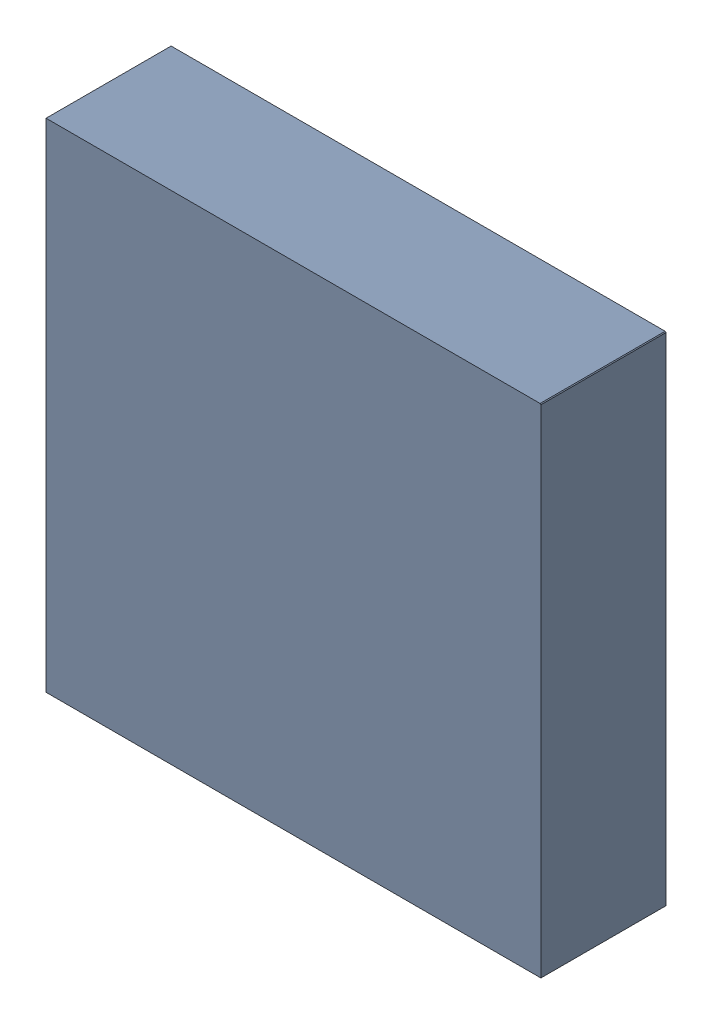
SolidWorks assembly U5, configuration 默认. Lengths in mm.
Overall size (3.17 3.19 0.82).
4 component instances, 2 part files, 0 mates.
Components (placement in the parent):
- 6641442208-1: 6641442208 [默认] at (8.4975 4.6 -2.7339) size (3.17 3.19 0.81)
  - Extruded-19-1: Extruded-19 [默认] at origin size (3.17 3.19 0.81)
- 6641441808-1: 6641441808 [默认] at (7.1852 5.8608 -2.7339) x (0 -1 0) z (0 0 -1) size (0.2 0.2 0.01)
  - Cylinder-20-1: Cylinder-20 [默认] at origin size (0.2 0.2 0.01)
